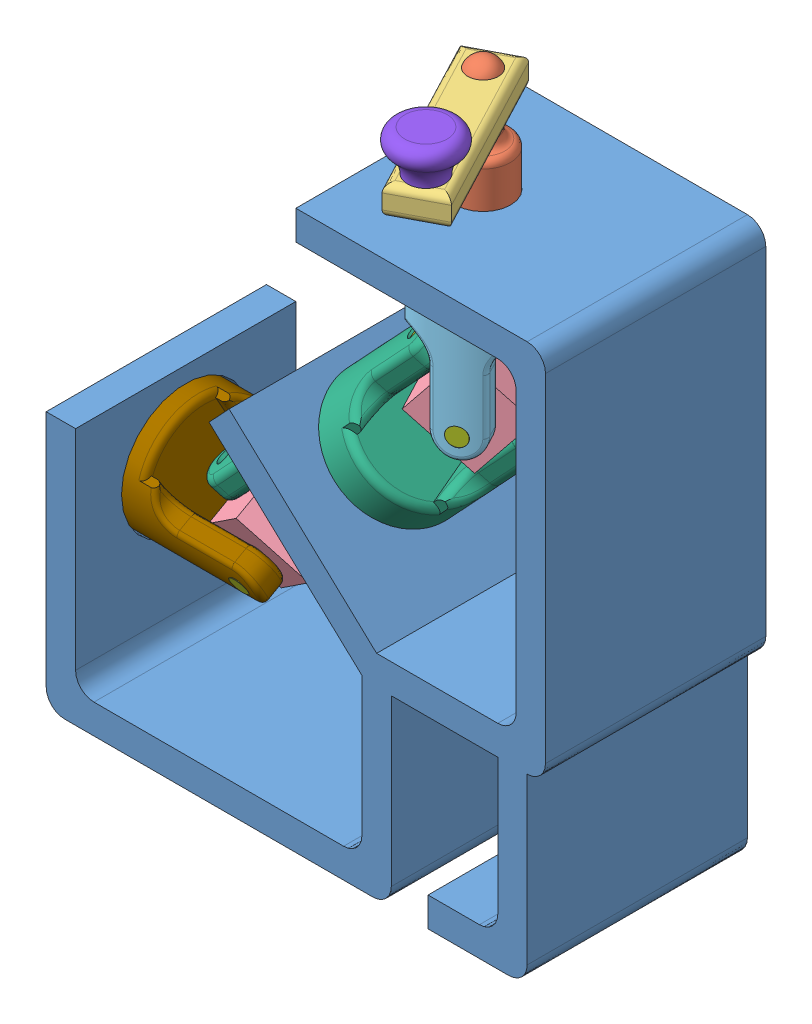
SolidWorks assembly double cardan joint, configuration Default. Lengths in mm.
Overall size (149.74 191.67 74.98).
11 component instances, 9 part files, 23 mates.
Components (placement in the parent):
- bracket-1: bracket [Default] at (81.6938 78.6621 159.1306) size (136 152 60)
- crank shaft-1: crank shaft [Default] at (84.6938 181.8732 159.1306) x (0.833801 0 0.552065) z (0 1 0) size (19.61 14.9 39.5)
- rocker arm-1: rocker arm [Default] at (93.0642 200.5445 175.066) x (0.465024 0 0.885298) z (-0.885298 0 0.465024) size (50 8 14)
- spider-4: spider [Default] at (32.236 76.7701 159.5276) x (0 0.489086 -0.872235) z (0.682427 -0.637563 -0.357499) size (19 19 19)
- spider-6: spider [Default] at (84.6938 132.8732 159.1306) x (-0.682427 0.637563 0.357499) z (-0.464045 0 -0.885812) size (19 19 19)
- yoke male 2-2: yoke male 2 [Default] at (84.6938 126.8732 159.1306) x (0.464045 0 0.885812) z (0 1 0) size (34 34 57)
- yoke female-1: yoke female [Default] at (58.6031 105.2151 159.1306) x (0.682427 -0.637563 -0.357499) z (0.261231 -0.244058 0.933913) size (35 90 35)
- Pin-1: Pin [Default] at (32.9938 84.3766 144.3026) x (0.682427 -0.637563 -0.357499) z (-0.730954 -0.595237 -0.333766) size (34 34 5)
- Pin-3: Pin [Default] at (73.0605 143.7118 165.1469) x (0.464045 0 0.885812) z (0.564761 0.770398 -0.295858) size (34 34 5)
- crank knob-1: crank knob [Default] at (101.8997 219.5445 191.8866) x (-0.809772 0 -0.586745) z (0 -1 0) size (17.51 17.51 18)
- yoke male2-1: yoke male2 [Default] at (38.9938 76.0621 159.1306) x (0 -0.489086 0.872235) z (-1 0 0) size (34 34 57.04)
Mates (geometry in assembly coordinates):
- Concentric5: concentric anti-aligned: cylinder of crank shaft-1 through (84.6938 206.8732 159.1306) axis (0 -1 0) radius 4; cylinder of rocker arm-1 through (84.6938 199.5445 159.1306) axis (0 1 0) radius 4
- Distance1: distance = 1.6713 mm anti-aligned: plane of rocker arm-1 through (93.0642 208.5445 175.066) normal (0 1 0); plane of crank shaft-1 through (84.6938 206.8732 159.1306) normal (0 -1 0)
- Angle1: planar angle = 0.523599 rad anti-aligned: plane of spider-5 through (-70.507 17.9195 50.1147) normal (-0.916726 0 -0.399517); plane of yoke male 2-1 through (-131.2282 2.9818 126.3946) normal (0.594149 0 0.804355)
- Distance6: distance = 0.5 mm anti-aligned: plane of spider-6 through (80.2854 132.8732 150.7154) normal (-0.464045 0 -0.885812); plane of yoke male 2-2 through (62.3371 126.8732 159.5534) normal (0.464045 0 0.885812)
- Concentric13: concentric anti-aligned: cylinder of spider-6 through (91.8865 132.8732 172.8607) axis (-0.464045 0 -0.885812) radius 2.5; cylinder of yoke male 2-2 through (73.0927 132.8732 136.9853) axis (0.464045 0 0.885812) radius 2.5
- Concentric14: concentric aligned: cylinder of crank shaft-1 through (84.6938 186.8732 159.1306) axis (0 -1 0) radius 4; cylinder of yoke male 2-2 through (84.6938 183.8732 159.1306) axis (0 -1 0) radius 4
- Concentric16: concentric aligned: cylinder of bracket-1 through (95.371 144.5703 159.1306) axis (-0.682679 -0.730718 0) radius 17.5; cylinder of yoke female-1 through (89.3236 138.0974 159.1306) axis (-0.682679 -0.730718 0) radius 17.5
- Concentric18: concentric anti-aligned: cylinder of bracket-1 through (84.6938 169.8732 159.1306) axis (0 1 0) radius 7.5; cylinder of crank shaft-1 through (84.6938 191.8732 159.1306) axis (0 -1 0) radius 7.45
- Coincident1: coincident aligned: plane of bracket-1 through (63.6938 171.8732 189.1306) normal (0 -1 0); plane of crank shaft-1 through (84.6938 171.8732 159.1306) normal (0 -1 0)
- Concentric19: concentric aligned: cylinder of crank shaft-1 through (84.6938 186.8732 159.1306) axis (0 -1 0) radius 4; cylinder of yoke male 2-2 through (84.6938 183.8732 159.1306) axis (0 -1 0) radius 4
- Coincident2: coincident anti-aligned: plane of bracket-1 through (63.6938 171.8732 189.1306) normal (0 -1 0); plane of yoke male 2-2 through (84.6938 171.8732 159.1306) normal (0 1 0)
- Concentric20: concentric anti-aligned: cylinder of yoke female-1 through (72.6024 144.1397 165.3868) axis (0.682427 -0.637563 -0.357499) radius 2.5; cylinder of pin-3 through (96.263 122.0346 152.9919) axis (-0.682427 0.637563 0.357499) radius 2.5
- Concentric21: concentric aligned: cylinder of spider-6 through (91.8865 132.8732 172.8607) axis (-0.464045 0 -0.885812) radius 2.5; cylinder of pin-3 through (92.5505 132.8732 174.1282) axis (-0.464045 0 -0.885812) radius 2.5
- Parallel11: parallel anti-aligned: plane of spider-6 through (79.1676 146.2488 151.301) normal (-0.682427 0.637563 0.357499); plane of yoke female-1 through (77.2748 149.3542 144.0273) normal (0.682427 -0.637563 -0.357499)
- Parallel17: parallel anti-aligned: plane of yoke female-1 through (29.4821 70.8383 136.8773) normal (-0.682427 0.637563 0.357499); plane of pin-1 through (44.5951 65.2235 153.0531) normal (0.682427 -0.637563 -0.357499)
- Width1: width aligned: plane of spider-4 through (25.753 82.8269 162.9238) normal (-0.682427 0.637563 0.357499); plane of spider-4 through (38.7191 70.7132 156.1313) normal (0.682427 -0.637563 -0.357499); plane of yoke female-1 through (29.4821 70.8383 136.8773) normal (-0.682427 0.637563 0.357499); plane of yoke female-1 through (15.8336 83.5896 144.0273) normal (0.682427 -0.637563 -0.357499)
- Concentric31: concentric aligned: cylinder of rocker arm-1 through (101.8997 199.5445 191.8866) axis (0 1 0) radius 2.5; cylinder of crank knob-1 through (101.8997 201.5445 191.8866) axis (0 1 0) radius 1.5
- Coincident3: coincident anti-aligned: plane of rocker arm-1 through (93.0642 208.5445 175.066) normal (0 1 0); plane of crank knob-1 through (101.8997 208.5445 191.8866) normal (0 -1 0)
- Concentric35: concentric anti-aligned: cylinder of spider-4 through (21.6584 86.6523 165.0688) axis (0.682427 -0.637563 -0.357499) radius 2.5; cylinder of pin-1 through (44.5951 65.2235 153.0531) axis (-0.682427 0.637563 0.357499) radius 2.5
- Concentric36: concentric anti-aligned: cylinder of bracket-1 through (53.1913 76.0621 159.1306) axis (-1 0 0) radius 17.5; cylinder of yoke male2-1 through (-6.0062 76.0621 159.1306) axis (1 0 0) radius 17
- Coincident4: coincident anti-aligned: plane of bracket-1 through (-4.3062 27.8732 189.1306) normal (-1 0 0); circle of yoke male2-1
- Concentric37: concentric anti-aligned: cylinder of Pin-1 through (32.9938 67.7476 173.9586) axis (0 0.489086 -0.872235) radius 2.5; cylinder of yoke male2-1 through (32.9938 88.2893 137.3247) axis (0 -0.489086 0.872235) radius 2.5
- Width2: width aligned: plane of yoke male2-1 through (38.9938 53.7265 158.0712) normal (0 0.489086 -0.872235); plane of yoke male2-1 through (38.9938 63.5083 140.6265) normal (0 -0.489086 0.872235); plane of spider-4 through (45.6631 81.0143 151.0159) normal (0 0.489086 -0.872235); plane of spider-4 through (45.6631 71.7216 167.5883) normal (0 -0.489086 0.872235)
